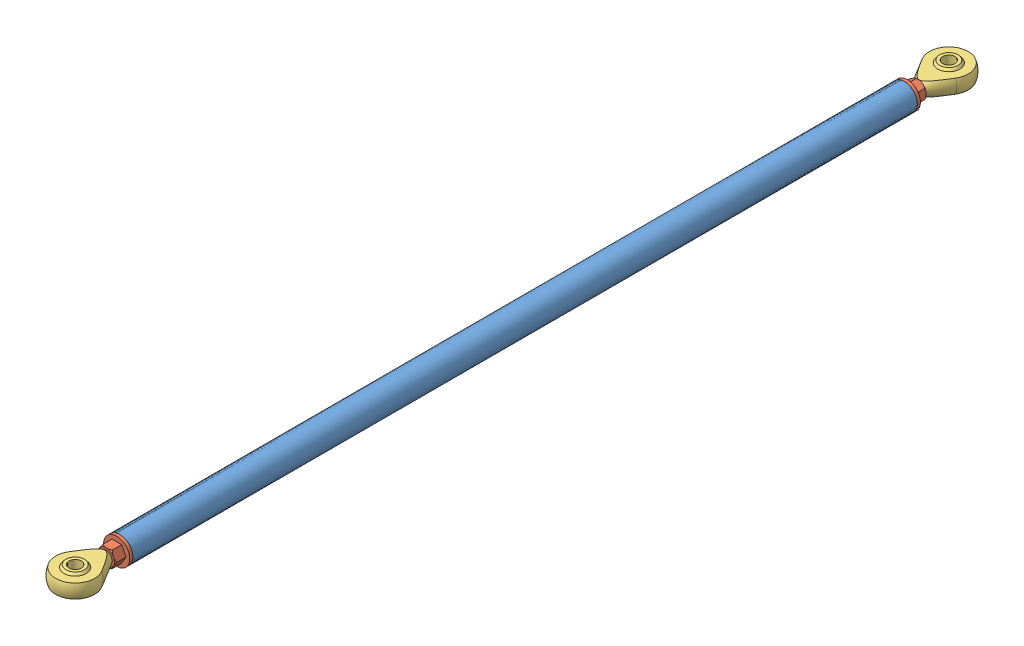
SolidWorks assembly PUTM-S-SF-RB_Pushrod, configuration Domyślna. Lengths in mm.
Overall size (20 17.46 443.48).
5 component instances, 3 part files, 10 mates.
Components (placement in the parent):
- PUTM-S-SF-RB-Carbon_Rod-1: PUTM-S-SF-RB-Carbon_Rod [Domyślna] at origin size (12.7 12.7 380.28)
- PUTM-S-SR-DS-ARB_inserty-1: PUTM-S-SR-DS-ARB_inserty [Domyślna] at (0 0 381.78) x (0 0 -1) z (0.852634 -0.522509 0) size (26.6 12.7 12.7)
- PUTM-S-SR-DS-ARB_inserty-2: PUTM-S-SR-DS-ARB_inserty [Domyślna] at (0 0 -1.5) x (0 0 1) z (0.51738 -0.855756 0) size (26.6 12.7 12.7)
- PUTM-S-rodenda-1: PUTM-S-rodenda [6mm] at (0 0 365.8803) x (0 1 0.000112) z (1 0 0) size (9 35.5 20)
- PUTM-S-rodenda-2: PUTM-S-rodenda [6mm] at (0 0 14.3997) x (0 -1 -0.000112) z (1 0 0) size (9 35.5 20)
Mates (geometry in assembly coordinates):
- Concentric2: concentric anti-aligned: cylinder of PUTM-S-SF-RB-Carbon_Rod-1 through (0 0 380.28) axis (0 0 -1) radius 5; cylinder of PUTM-S-SR-DS-ARB_inserty-1 through (0 0 381.78) axis (0 0 1) radius 5
- Coincident1: coincident anti-aligned: plane of PUTM-S-SF-RB-Carbon_Rod-1 through (0 0 380.28) normal (0 0 1); plane of PUTM-S-SR-DS-ARB_inserty-1 through (-5.4142 3.3179 380.28) normal (0 0 -1)
- Concentric4: concentric aligned: cylinder of PUTM-S-SF-RB-Carbon_Rod-1 through (0 0 380.28) axis (0 0 -1) radius 5; cylinder of PUTM-S-SR-DS-ARB_inserty-2 through (0 0 -1.5) axis (0 0 -1) radius 5
- Coincident2: coincident anti-aligned: plane of PUTM-S-SF-RB-Carbon_Rod-1 through (0 0 0) normal (0 0 -1); plane of PUTM-S-SR-DS-ARB_inserty-2 through (-3.2854 5.434 0) normal (0 0 1)
- Concentric5: concentric anti-aligned: cylinder of PUTM-S-SR-DS-ARB_inserty-1 through (0 0 381.78) axis (0 0 1) radius 2.46; cone of PUTM-S-rodenda-1 through (0 0 386.88) axis (0 0 -1)
- Concentric10: concentric anti-aligned: cylinder of PUTM-S-SR-DS-ARB_inserty-2 through (0 0 -1.5) axis (0 0 -1) radius 2.46; cone of PUTM-S-rodenda-2 through (0 0 -6.6) axis (0 0 1)
- Parallel1: parallel anti-aligned: line of PUTM-S-rodenda-1 through (0 -1.004 401.8796) axis (0 1 0.000112); line of PUTM-S-rodenda-2 through (0 1.004 -21.5996) axis (0 -1 -0.000112)
- Parallel2: parallel: line of PUTM-S-rodenda-1 through (0 -1.004 401.8796) axis (0 1 0.000112)
- ProfileCenter3: profile center anti-aligned: circle of PUTM-S-rodenda-2; circle of PUTM-S-SR-DS-ARB_inserty-2
- ProfileCenter4: profile center anti-aligned: circle of PUTM-S-rodenda-1; circle of PUTM-S-SR-DS-ARB_inserty-1
